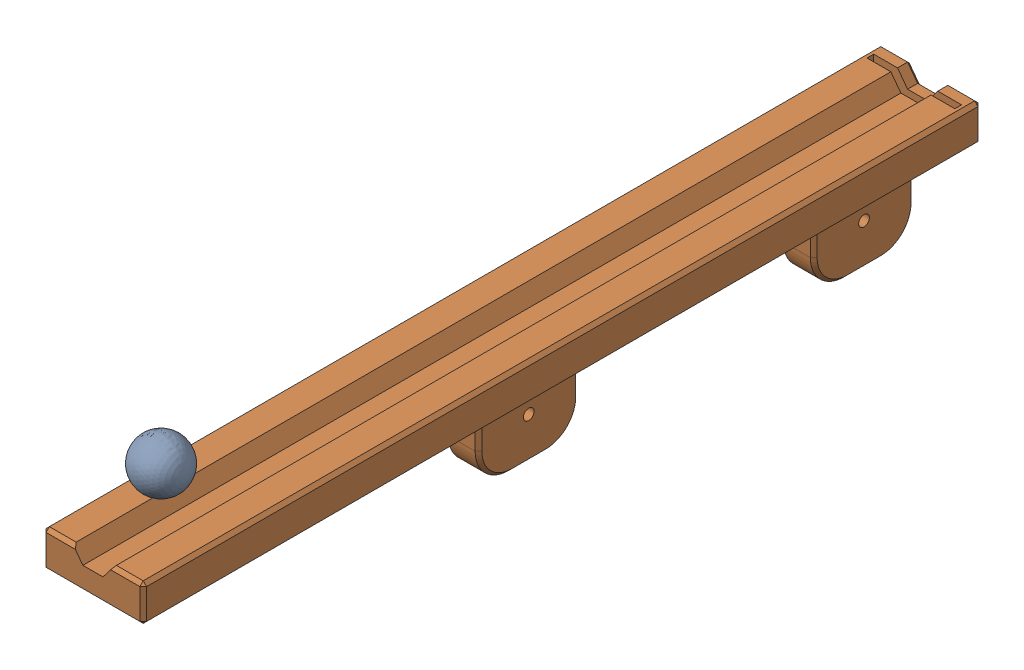
SolidWorks assembly 15mm ball and platform assemble, configuration Default. Lengths in mm.
Overall size (30 58.46 250).
2 component instances, 2 part files, 0 mates.
Components (placement in the parent):
- 15mm ball-1: 15mm ball [預設] at (-10.3471 4.2447 6.1031) size (15 15 15)
- platform-1: platform [預設] at (3.3428 -21.7109 25.1059) x (0 0 -1) z (0 1 0) size (250 30 36)
